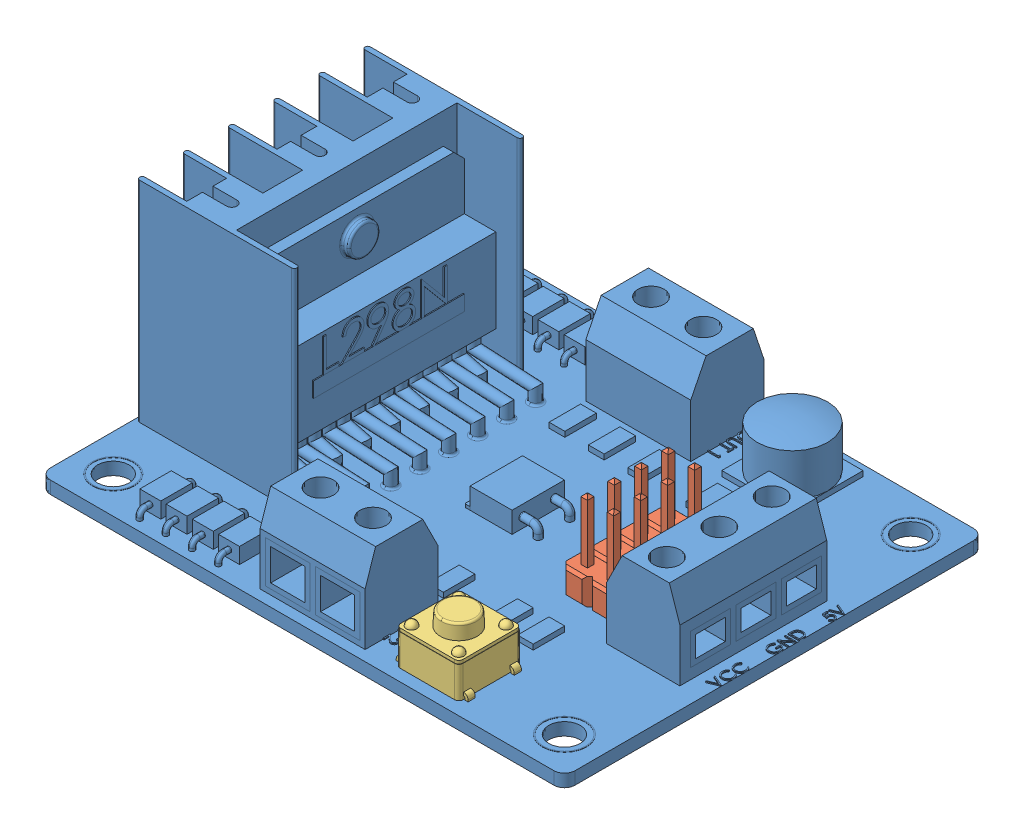
SolidWorks assembly L298n, configuration Default. Lengths in mm.
Overall size (50.07 23.81 40).
3 component instances, 3 part files, 0 mates.
Components (placement in the parent):
- l298n-1: l298n [Default] at (-2.7525 -2.0926 3.7643) size (50.07 21.2 40)
- HDR2x4-1: HDR2x4 [Default] at (8.4133 -0.8926 0.0344) x (-0.011181 0 0.999937) z (-0.999937 0 -0.011181) size (10.16 12.19 5.08)
- Tact DIP 6x6-1: Tact DIP 6x6 [Default] at (8.0516 -1.1926 19.6395) size (6.85 7 6)
